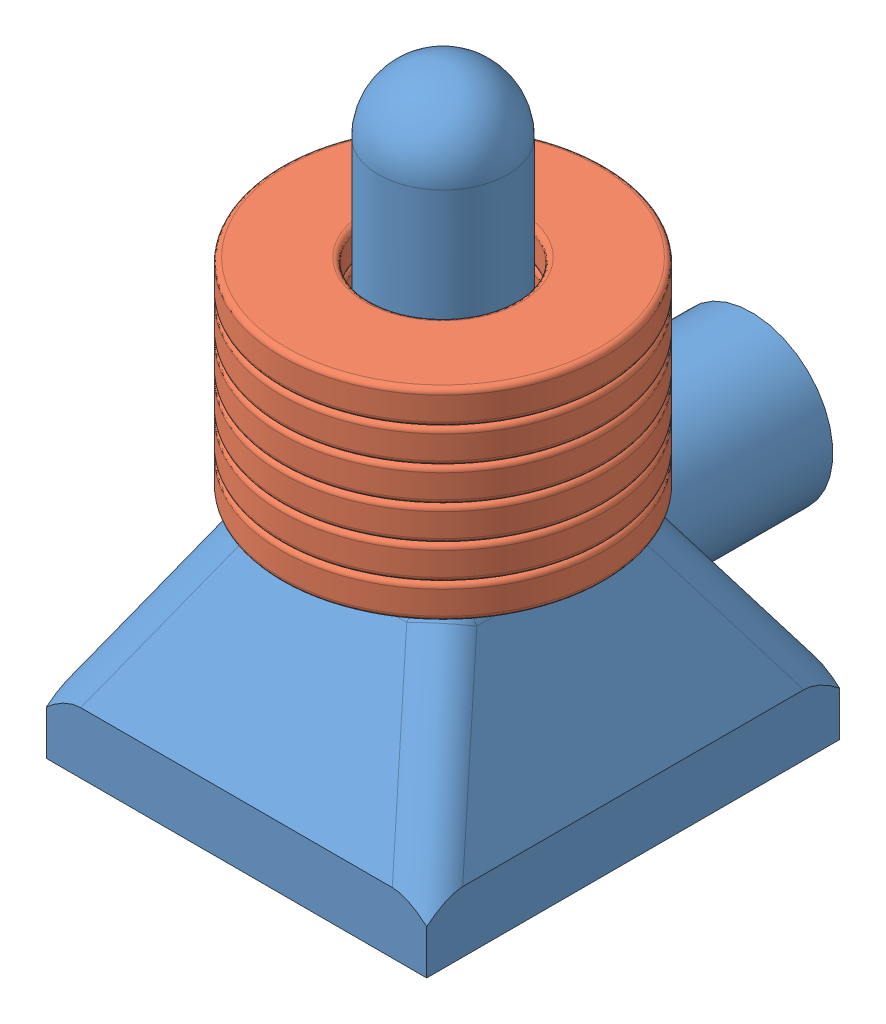
SolidWorks assembly vc_pickup_asm, configuration Default. Lengths in mm.
Overall size (18.67 29.18 25.27).
7 component instances, 2 part files, 3 mates.
Components (placement in the parent):
- vc_pickup-1: vc_pickup [Default] at origin size (18.67 29.18 25.27)
- washer 1-4-1: washer 1-4 [Default] at (0 11 0) size (15.88 1.65 15.88)
- washer 1-4-2: washer 1-4 [Default] at (0 12.651 0) size (15.88 1.65 15.88)
- washer 1-4-3: washer 1-4 [Default] at (0 14.302 0) size (15.88 1.65 15.88)
- washer 1-4-4: washer 1-4 [Default] at (0 15.953 0) size (15.88 1.65 15.88)
- washer 1-4-5: washer 1-4 [Default] at (0 17.604 0) size (15.88 1.65 15.88)
- washer 1-4-6: washer 1-4 [Default] at (0 19.255 0) size (15.88 1.65 15.88)
Mates (geometry in assembly coordinates):
- Coincident1: coordinate: point of vc_pickup-1; point of assembly
- Coincident2: coincident anti-aligned: plane of vc_pickup-1 through (-5 11 5) normal (0 1 0); plane of washer 1-4-1 through (0 11 0) normal (0 -1 0)
- Concentric1: concentric aligned: cylinder of vc_pickup-1 through (0 26 0) axis (0 -1 0) radius 3.175; cylinder of washer 1-4-1 through (0 12.651 0) axis (0 -1 0) radius 7.9375
